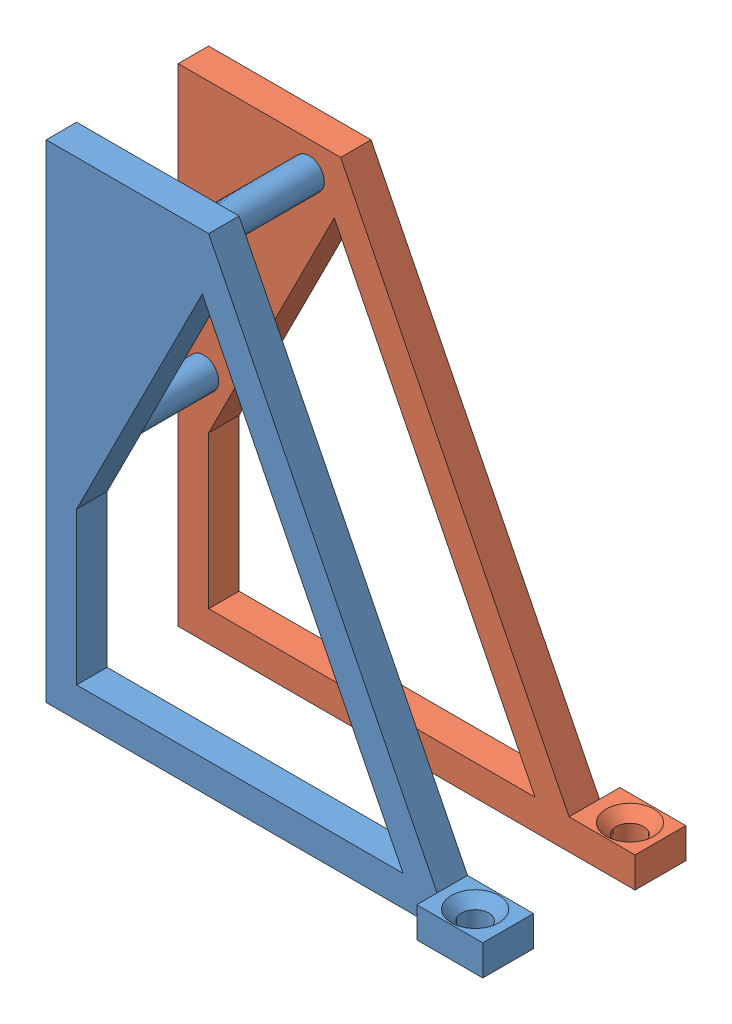
SolidWorks assembly Sestava1, configuration Výchozí. Lengths in mm.
Overall size (45 48 20).
2 component instances, 2 part files, 1 mates.
Components (placement in the parent):
- holder_base-1: holder_base [Výchozí] at (-54.7621 -25.1387 48) size (45 48 18)
- holder_other_side-1: holder_other_side [Výchozí] at (-54.7621 -25.1387 35) size (45 48 5)
Mates (geometry in assembly coordinates):
- Sjednocená1: coincident anti-aligned: circle of holder_base-1; circle of holder_other_side-1
